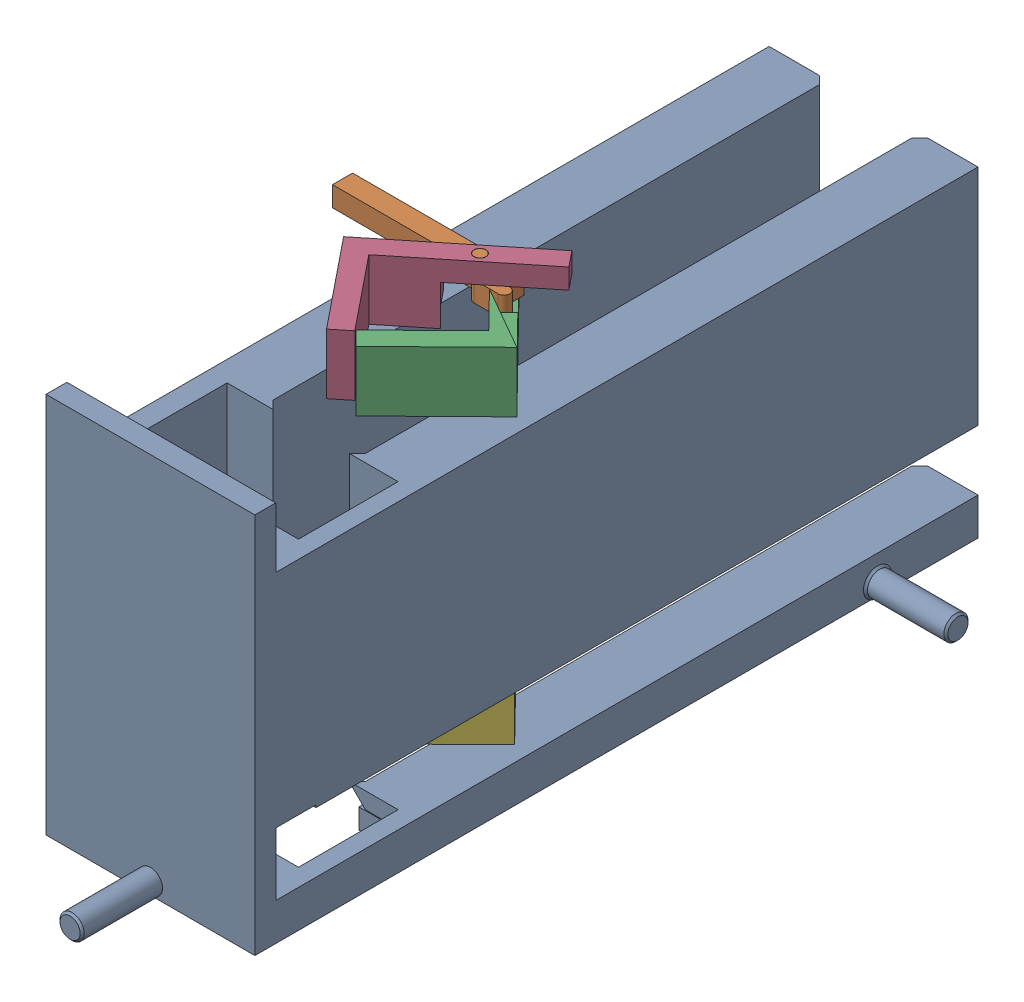
SolidWorks assembly 装配体6, configuration 默认. Lengths in mm.
Overall size (92 95 200).
9 component instances, 3 part files, 2 mates.
Components (placement in the parent):
- 上推-1: 上推 [默认] at (-13.7334 -39.3617 -100) size (92 95 200)
- 装配体40SLDASM-1: 装配体40SLDASM [默认] at (-16.1244 50.6383 -4.409) x (1 0 0) z (0 -1 0) size (63.3 51.73 15)
  - center-1: center [默认] at origin size (45.59 7.9 15)
  - left-1: left [默认] at (1.46 -1.0612 10) x (-0.999948 -0.010157 0) z (0 0 -1) size (32.11 48.61 15)
  - left-2: left [默认] at (4.6325 -0.5275 -5) x (0.994379 0.105881 0) z (0 0 1) size (32.11 48.61 15)
- 装配体40SLDASM-2: 装配体40SLDASM [默认] at (-16.4435 -20.0775 -4.1734) x (1 0 0) z (0 -1 0) size (63.3 51.73 15)
  - center-1: center [默认] at origin size (45.59 7.9 15)
  - left-1: left [默认] at (1.46 -1.0612 10) x (-0.999948 -0.010157 0) z (0 0 -1) size (32.11 48.61 15)
  - left-2: left [默认] at (4.6325 -0.5275 -5) x (0.994379 0.105881 0) z (0 0 1) size (32.11 48.61 15)
Mates (geometry in assembly coordinates):
- 重合1: coincident anti-aligned: plane of 上推-1 through (-127.7334 40.6383 -100) normal (0 1 0); plane of 装配体40SLDASM-1/left-1 through (-14.6644 40.6383 -5.4702) normal (0 -1 0)
- 重合2: coincident anti-aligned: plane of 上推-1 through (-127.7334 -30.0775 -100) normal (0 1 0); plane of 装配体40SLDASM-2/left-1 through (-14.9835 -30.0775 -5.2346) normal (0 -1 0)
